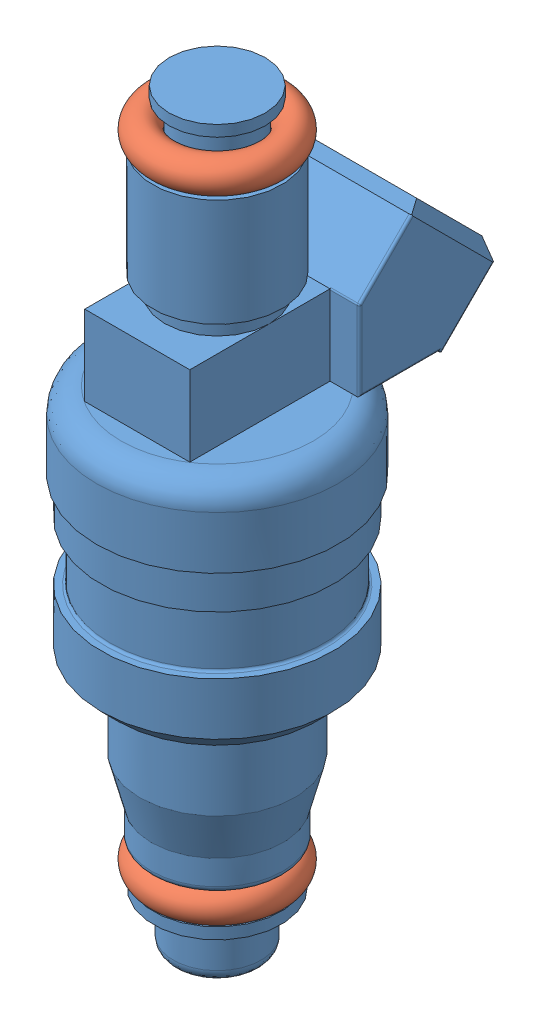
SolidWorks assembly 2010_injectors, configuration Default. Lengths in mm.
Overall size (24.92 77.22 32.6).
3 component instances, 2 part files, 4 mates.
Components (placement in the parent):
- 2010_injectors-1: 2010_injectors [Default] at (-2.9117 -22.1408 16.5786) size (24.92 77.22 32.6)
- Injector_o-ring-1: Injector_o-ring [AS568 - 011] at (-2.9117 51.1382 16.5786) x (-0.537903 0 -0.843006) z (-0.843006 0 0.537903) size (14.48 3.3 14.48)
- Injector_o-ring-2: Injector_o-ring [AS568 - 011] at (-2.9117 -14.0636 16.5786) x (0.996935 0 0.078229) z (-0.078229 0 0.996935) size (14.48 3.3 14.48)
Mates (geometry in assembly coordinates):
- Coincident2: coincident anti-aligned: line of 2010_injectors-1 through (-2.9117 58.936 16.5786) axis (0 -1 0); line of Injector_o-ring-2 through (-2.9117 -18.9467 16.5786) axis (0 1 0)
- Coincident3: coincident aligned: line of Injector_o-ring-1 through (-2.9117 50.8103 16.5786) axis (0 -1 0); line of 2010_injectors-1 through (-2.9117 58.936 16.5786) axis (0 -1 0)
- Tangent4: tangent: plane of 2010_injectors-1 through (0.9745 -12.4126 16.5786) normal (0 -1 0); face of Injector_o-ring-2
- Tangent5: tangent: plane of 2010_injectors-1 through (0.9618 49.4872 16.5786) normal (0 1 0); face of Injector_o-ring-1
